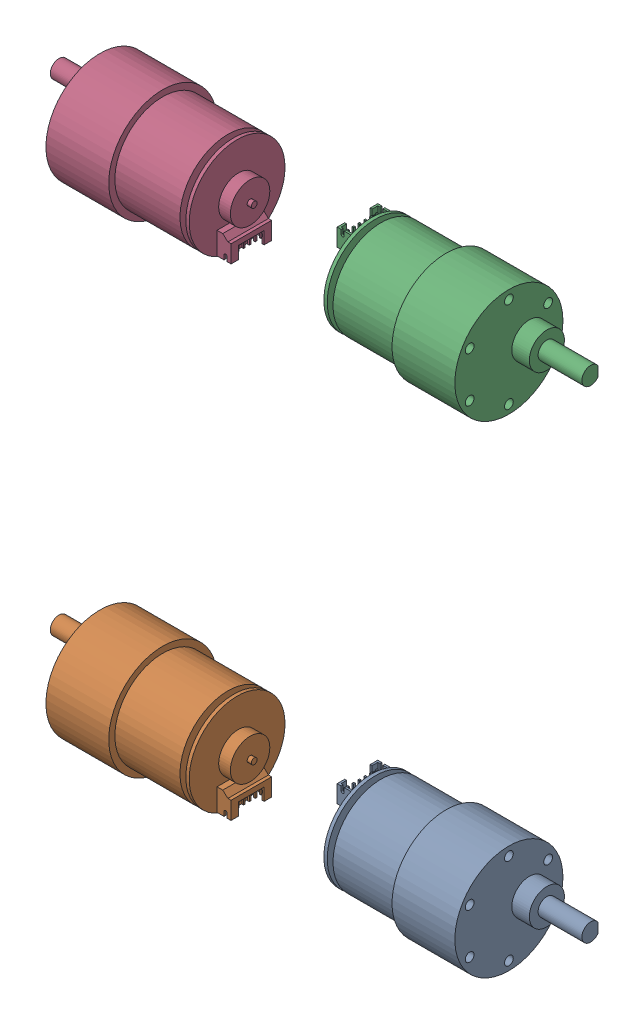
SolidWorks assembly Motors-1, configuration Varsayılan. Lengths in mm.
Overall size (182 202 37).
4 component instances, 4 part files, 0 mates.
Components (placement in the parent):
- DC Gear Motor 37mm_001-1-1: DC Gear Motor 37mm_001-1 [Varsayılan] at (79 -115.5 -28.5) x (0 0 -1) z (1 0 0) size (37 37 73.8)
- DC Gear Motor 37mm_002-1-1: DC Gear Motor 37mm_002-1 [Varsayılan] at (-79 -115.5 -28.5) x (0 0 -1) z (-1 0 0) size (37 37 73.8)
- DC Gear Motor 37mm_003-1-1: DC Gear Motor 37mm_003-1 [Varsayılan] at (79 49.5 -28.5) x (0 0 -1) z (1 0 0) size (37 37 73.8)
- DC Gear Motor 37mm_004-1-1: DC Gear Motor 37mm_004-1 [Varsayılan] at (-79 49.5 -28.5) x (0 0 -1) z (-1 0 0) size (37 37 73.8)
